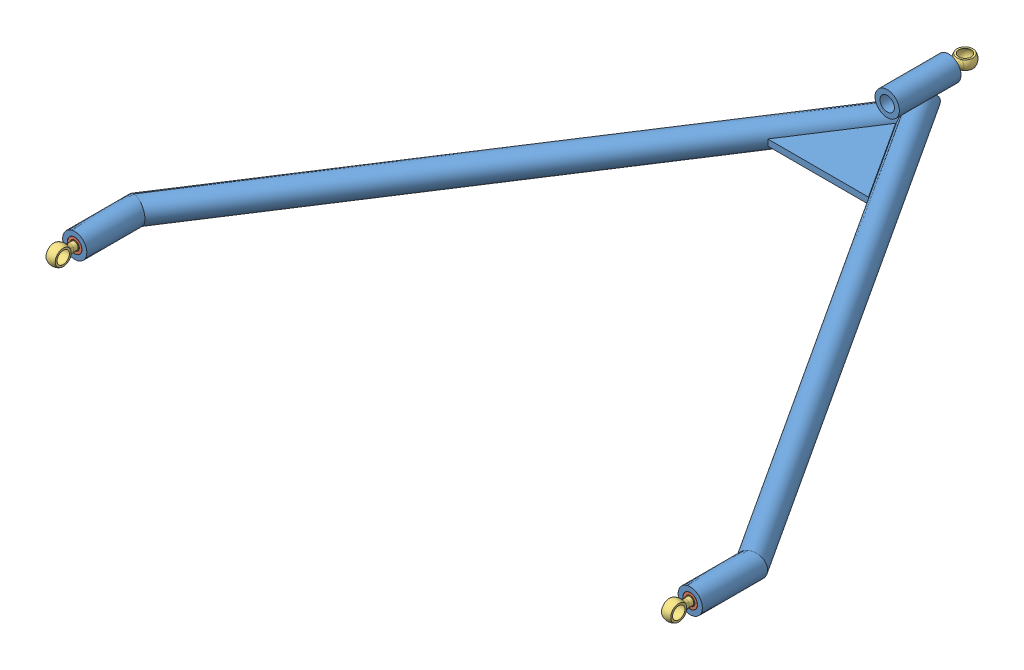
SolidWorks assembly Front Wishbone Final, configuration Default. Lengths in mm.
Overall size (415.24 31.6 400.45).
10 component instances, 3 part files, 8 mates.
Components (placement in the parent):
- front wishbones-1: front wishbones [Default<As Machined>] at (192.2081 228.8628 121.6906) size (415.24 31.6 367.54)
- rod end screw cap assembly-1: rod end screw cap assembly [Default] at (383.9127 116.3972 402.8295) x (0 -1 0) z (0 0 1) size (12 9.2 41.45)
  - rod end screw cap-1: rod end screw cap [Default] at (-112.4655 8.0145 66.4016) size (9.2 9.2 25)
  - Pushrod screw-1: Pushrod screw [Default] at (-112.4655 8.0145 76.856) x (0 0 -1) z (1 0 0) size (36.45 6 12)
- rod end screw cap assembly-2: rod end screw cap assembly [Default] at (79.7426 236.6482 168.0922) x (-1 0 0) z (0 0 -1) size (12 9.2 41.45)
  - rod end screw cap-1: rod end screw cap [Default] at (-112.4655 8.0145 66.4016) size (9.2 9.2 25)
  - Pushrod screw-1: Pushrod screw [Default] at (-112.4655 8.0145 76.856) x (0 0 -1) z (1 0 0) size (36.45 6 12)
- rod end screw cap assembly-3: rod end screw cap assembly [Default] at (-15.5255 116.3972 402.8295) x (0 -1 0) z (0 0 1) size (12 9.2 41.45)
  - rod end screw cap-1: rod end screw cap [Default] at (-112.4655 8.0145 66.4016) size (9.2 9.2 25)
  - Pushrod screw-1: Pushrod screw [Default] at (-112.4655 8.0145 76.856) x (0 0 -1) z (1 0 0) size (36.45 6 12)
Mates (geometry in assembly coordinates):
- Coincident1: coincident anti-aligned: line of front wishbones-1 through (-7.511 228.8628 429.2311) axis (0 0 1); line of rod end screw cap assembly-3/Pushrod screw-1 through (-7.511 228.8628 479.6855) axis (0 0 -1)
- Coincident2: coincident anti-aligned: line of front wishbones-1 through (391.9272 228.8628 429.2311) axis (0 0 1); line of rod end screw cap assembly-1/Pushrod screw-1 through (391.9272 228.8628 479.6855) axis (0 0 -1)
- Coincident3: coincident: axis of front wishbones-1 through (192.2081 244.6628 141.6906) axis (0 0 -1); line of rod end screw cap assembly-2/Pushrod screw-1 through (192.2081 244.6628 91.2363) axis (0 0 1)
- Coincident4: coincident aligned: plane of front wishbones-1 through (391.9272 228.8628 469.2311) normal (0 0 1); plane of rod end screw cap assembly-1/rod end screw cap-1 through (391.9272 228.8628 469.2311) normal (0 0 1)
- Coincident5: coincident aligned: plane of front wishbones-1 through (-7.511 228.8628 469.2311) normal (0 0 1); plane of rod end screw cap assembly-3/rod end screw cap-1 through (-7.511 228.8628 469.2311) normal (0 0 1)
- Coincident6: coincident: plane of front wishbones-1 through (192.2081 228.8628 101.6906) normal (0 0 -1); plane of rod end screw cap assembly-2/rod end screw cap-1 through (192.2081 244.6628 101.6906) normal (0 0 -1)
- Concentric1: concentric aligned: circle of rod end screw cap assembly-1/Pushrod screw-1; circle of rod end screw cap assembly-3/Pushrod screw-1
- Perpendicular1: perpendicular: plane of front wishbones-1 through (192.2081 230.8628 121.6906) normal (0 1 0); axis of rod end screw cap assembly-2/Pushrod screw-1 through (192.2081 247.7352 91.2363) axis (0 -1 0)
